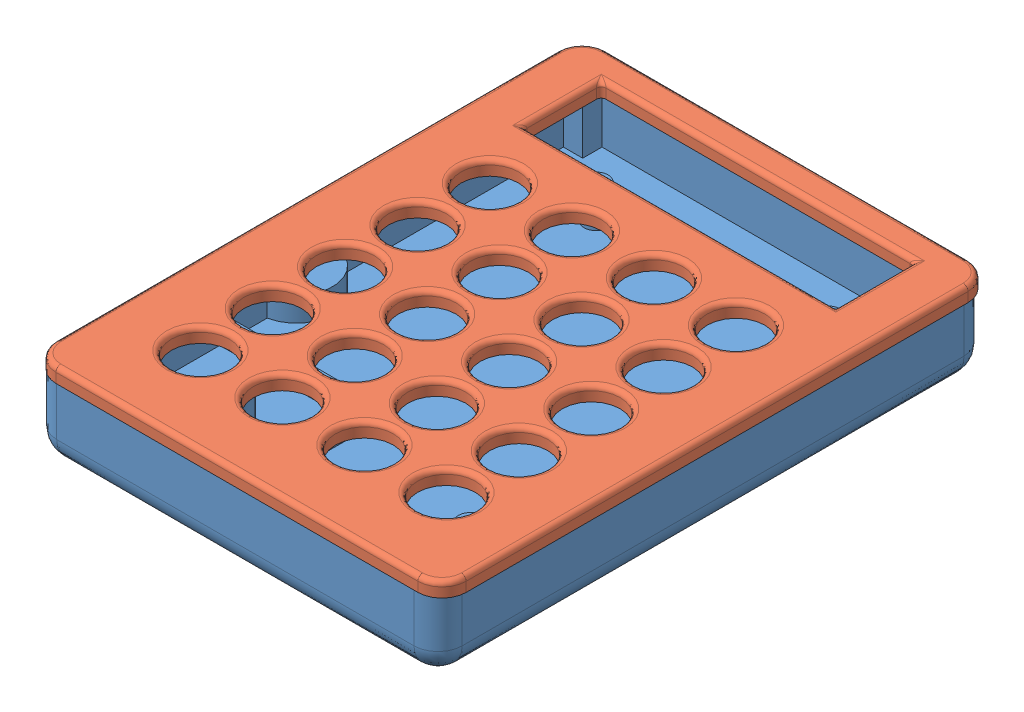
SolidWorks assembly Assem2, configuration Default. Lengths in mm.
Overall size (85 18 114).
2 component instances, 2 part files, 2 mates.
Components (placement in the parent):
- Part3-1: Part3 [Default] at (5.9361 44.7923 146.5468) size (84.03 15 114)
- Part4-1: Part4 [Default] at (48.285 59.7923 89.5468) x (0 0 -1) z (1 0 0) size (114 3 85)
Mates (geometry in assembly coordinates):
- Coincident1: coincident anti-aligned: plane of Part3-1 through (5.9361 59.7923 146.5468) normal (0 1 0); plane of Part4-1 through (48.285 59.7923 89.5468) normal (0 -1 0)
- Coincident4: coincident aligned: plane of Part3-1 through (5.9361 59.7923 32.5468) normal (0 0 -1); plane of Part4-1 through (90.785 62.7923 32.5468) normal (0 0 -1)
